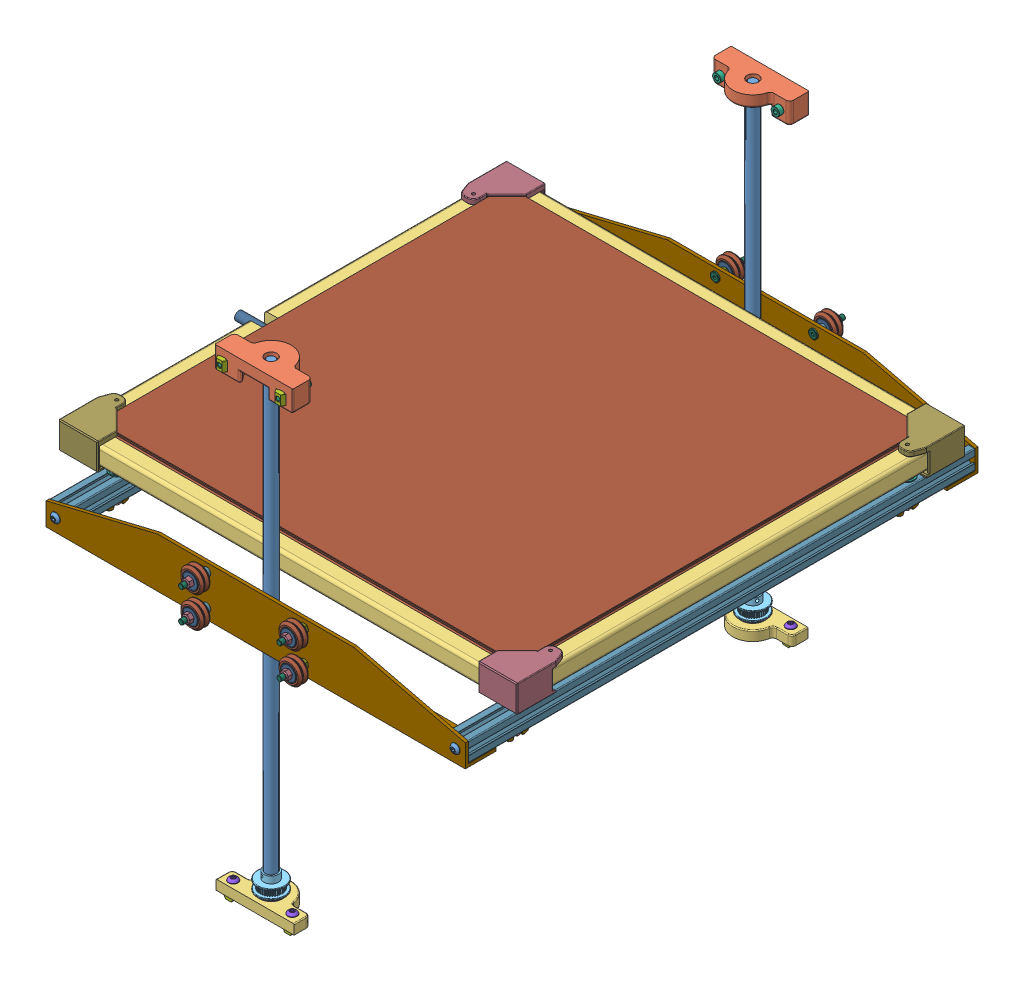
SolidWorks assembly Z_Bed_Assembly, configuration Default. Lengths in mm.
Overall size (485 491.92 579.5).
165 component instances, 32 part files, 17 mates.
Components (placement in the parent):
- Z_Axis_Module-1: Z_Axis_Module [Default] at origin size (80 491.92 43.77)
  - 12mm_Leadscrew-1: 12mm_Leadscrew [Default] at (0 243.6 0) x (0.985154 0 0.171673) z (-0.171673 0 0.985154) size (12 480 12)
  - Z_Leadscrew_Bearing_Holder_Top-1: Z_Leadscrew_Bearing_Holder_Top [Default] at (0 485.6 0) x (-1 0 0) z (0 0 1) size (80 22.17 38.27)
  - Z_Leadscrew_Bearing_Holder_Base-1: Z_Leadscrew_Bearing_Holder_Base [Default] at origin size (80 10 37)
  - 6082Z-8x22x7-1: 6082Z-8x22x7 [6082Z-8x22x7] at (0 480.6 0) x (-0.837169 0 -0.546944) z (0 -1 0) size (22 22 7)
  - 6082Z-8x22x7-2: 6082Z-8x22x7 [6082Z-8x22x7] at (0 4 0) x (1 0 0) z (0 1 0) size (22 22 7)
  - GT2_Aluminum_Timing_Pulley_36_Tooth-1: GT2_Aluminum_Timing_Pulley_36_Tooth [Default] at (0 29.6 0) x (-0.337691 0 0.941257) z (0.941257 0 0.337691) size (28.13 17.5 28.13)
  - 5mmX25mm_Sockethead(McMaster_91290A252)-1: 5mmX25mm_Sockethead(McMaster_91290A252) [91290A252] at (30 474.6 22.7241) size (8.5 8.5 30.5)
  - 5mmX25mm_Sockethead(McMaster_91290A252)-2: 5mmX25mm_Sockethead(McMaster_91290A252) [91290A252] at (-30 474.6 22.7241) size (8.5 8.5 30.5)
  - HNTTSN5-5-1: HNTTSN5-5 [Default] at (-30 474.6 18.9241) x (0 0 -1) z (0 1 0) size (4.3 10 10)
  - HNTTSN5-5-2: HNTTSN5-5 [Default] at (30 474.6 18.9241) x (0 0 -1) z (0 1 0) size (4.3 10 10)
  - HNTTSN5-5-3: HNTTSN5-5 [Default] at (-29.9966 -1.2 8.862) x (0 1 0) z (0 0 1) size (4.3 10 10)
  - HNTTSN5-5-4: HNTTSN5-5 [Default] at (30 -1.2 8.2271) x (0 1 0) z (0 0 1) size (4.3 10 10)
  - 5mmX16mm_Buttonhead(McMaster_91239A232)-1: 5mmX16mm_Buttonhead(McMaster_91239A232) [91239A232] at (30 12.75 8.2271) x (0.745488 0 0.666519) z (0 1 0) size (9.5 9.5 19.24)
  - 5mmX16mm_Buttonhead(McMaster_91239A232)-2: 5mmX16mm_Buttonhead(McMaster_91239A232) [91239A232] at (-29.9966 12.75 8.862) x (0.982416 0 0.186707) z (0 1 0) size (9.5 9.5 19.24)
- Z_Axis_Module-2: Z_Axis_Module [Default] at (0 0 -494.1) x (-1 0 0) z (0 0 -1) size (80 491.92 43.77)
  - 12mm_Leadscrew-1: 12mm_Leadscrew [Default] at (0 243.6 0) x (0.985154 0 0.171673) z (-0.171673 0 0.985154) size (12 480 12)
  - Z_Leadscrew_Bearing_Holder_Top-1: Z_Leadscrew_Bearing_Holder_Top [Default] at (0 485.6 0) x (-1 0 0) z (0 0 1) size (80 22.17 38.27)
  - Z_Leadscrew_Bearing_Holder_Base-1: Z_Leadscrew_Bearing_Holder_Base [Default] at origin size (80 10 37)
  - 6082Z-8x22x7-1: 6082Z-8x22x7 [6082Z-8x22x7] at (0 480.6 0) x (-0.837169 0 -0.546944) z (0 -1 0) size (22 22 7)
  - 6082Z-8x22x7-2: 6082Z-8x22x7 [6082Z-8x22x7] at (0 4 0) x (1 0 0) z (0 1 0) size (22 22 7)
  - GT2_Aluminum_Timing_Pulley_36_Tooth-1: GT2_Aluminum_Timing_Pulley_36_Tooth [Default] at (0 29.6 0) x (-0.337691 0 0.941257) z (0.941257 0 0.337691) size (28.13 17.5 28.13)
  - 5mmX25mm_Sockethead(McMaster_91290A252)-1: 5mmX25mm_Sockethead(McMaster_91290A252) [91290A252] at (30 474.6 22.7241) size (8.5 8.5 30.5)
  - 5mmX25mm_Sockethead(McMaster_91290A252)-2: 5mmX25mm_Sockethead(McMaster_91290A252) [91290A252] at (-30 474.6 22.7241) size (8.5 8.5 30.5)
  - HNTTSN5-5-1: HNTTSN5-5 [Default] at (-30 474.6 18.9241) x (0 0 -1) z (0 1 0) size (4.3 10 10)
  - HNTTSN5-5-2: HNTTSN5-5 [Default] at (30 474.6 18.9241) x (0 0 -1) z (0 1 0) size (4.3 10 10)
  - HNTTSN5-5-3: HNTTSN5-5 [Default] at (-29.9966 -1.2 8.862) x (0 1 0) z (0 0 1) size (4.3 10 10)
  - HNTTSN5-5-4: HNTTSN5-5 [Default] at (30 -1.2 8.2271) x (0 1 0) z (0 0 1) size (4.3 10 10)
  - 5mmX16mm_Buttonhead(McMaster_91239A232)-1: 5mmX16mm_Buttonhead(McMaster_91239A232) [91239A232] at (30 12.75 8.2271) x (0.745488 0 0.666519) z (0 1 0) size (9.5 9.5 19.24)
  - 5mmX16mm_Buttonhead(McMaster_91239A232)-2: 5mmX16mm_Buttonhead(McMaster_91239A232) [91239A232] at (-29.9966 12.75 8.862) x (0.982416 0 0.186707) z (0 1 0) size (9.5 9.5 19.24)
- Z_Gantry_Angle_Plate-1: Z_Gantry_Angle_Plate [Default] at (0 234.9034 15.875) x (-1 0 0) z (0 0 1) size (430 66.25 58.58)
  - Z_Gantry_Plate-1: Z_Gantry_Plate [Default] at origin size (430 50.8 31.75)
  - Dual_V_Wheel_Bolt_Assembly-1: Dual_V_Wheel_Bolt_Assembly [Default] at (50 -42.8 -4.675) x (-0.831081 0.556151 0) z (0.556151 0.831081 0) size (24.11 31.5 24.11) (flexible)
    - Ball_Bearing_625_2RS-1: Ball_Bearing_625_2RS [Défaut] at (0 13.525 0) x (-1 0 0) z (0 0 1) size (16 5 16)
    - Ball_Bearing_625_2RS-2: Ball_Bearing_625_2RS [Défaut] at (0 19.525 0) x (-0.965595 0 -0.260051) z (-0.260051 0 0.965595) size (16 5 16)
    - Dual_V_Wheel_Delrin_(5mm_Bore)-1: Dual_V_Wheel_Delrin_(5mm_Bore) [Défaut] at (0 11.41 0) x (0.999956 0 0.009415) z (-0.009415 0 0.999956) size (23.89 10.23 23.89)
    - Precision_Shim_10x5x1mm-1: Precision_Shim_10x5x1mm [Default] at (0 16.525 0) x (-0.674323 0 -0.738436) z (-0.738436 0 0.674323) size (10 1 10)
    - Nylon_Insert_Hex_Locknut_5mm-1: Nylon_Insert_Hex_Locknut_5mm [Default] at (0 22.025 0) x (0.336542 0 0.941668) z (-0.941668 0 0.336542) size (8 4.99 9.24)
    - Aluminium_Spacer-1: Aluminium_Spacer [Défaut] at (0 7.85 0) x (-0.619579 0 0.784934) z (0 -1 0) size (8 8 6.35)
    - M5_Low_Profile_Screw_30mm-1: M5_Low_Profile_Screw_30mm [Default] at origin size (9 31.5 9)
  - Dual_V_Wheel_Bolt_Assembly-2: Dual_V_Wheel_Bolt_Assembly [Default] at (50 -11.175 -4.675) x (0.333901 -0.942608 0) z (-0.942608 -0.333901 0) size (29.34 31.5 29.34) (flexible)
    - Ball_Bearing_625_2RS-1: Ball_Bearing_625_2RS [Défaut] at (0 13.525 0) x (-1 0 0) z (0 0 1) size (16 5 16)
    - Ball_Bearing_625_2RS-2: Ball_Bearing_625_2RS [Défaut] at (0 19.525 0) x (-0.965595 0 -0.260051) z (-0.260051 0 0.965595) size (16 5 16)
    - Dual_V_Wheel_Delrin_(5mm_Bore)-1: Dual_V_Wheel_Delrin_(5mm_Bore) [Défaut] at (0 11.41 0) x (0.964694 0 -0.263375) z (0.263375 0 0.964694) size (23.89 10.23 23.89)
    - Precision_Shim_10x5x1mm-1: Precision_Shim_10x5x1mm [Default] at (0 16.525 0) x (-0.674323 0 -0.738436) z (-0.738436 0 0.674323) size (10 1 10)
    - Nylon_Insert_Hex_Locknut_5mm-1: Nylon_Insert_Hex_Locknut_5mm [Default] at (0 22.025 0) x (0.457359 0 0.889282) z (-0.889282 0 0.457359) size (8 4.99 9.24)
    - Aluminium_Spacer-1: Aluminium_Spacer [Défaut] at (0 7.85 0) x (0.780963 0 0.624577) z (0 -1 0) size (8 8 6.35)
    - M5_Low_Profile_Screw_30mm-1: M5_Low_Profile_Screw_30mm [Default] at origin size (9 31.5 9)
  - Dual_V_Wheel_Bolt_Assembly_Eccentric-1: Dual_V_Wheel_Bolt_Assembly_Eccentric [Default] at (-50.7692 -11.3552 -4.675) x (1 0 0) z (0 -1 0) size (27.28 31.5 27.28) (flexible)
    - Ball_Bearing_625_2RS-1: Ball_Bearing_625_2RS [Défaut] at (0 13.525 0) x (-1 0 0) z (0 0 1) size (16 5 16)
    - Ball_Bearing_625_2RS-2: Ball_Bearing_625_2RS [Défaut] at (0 19.525 0) x (-0.965595 0 -0.260051) z (-0.260051 0 0.965595) size (16 5 16)
    - Dual_V_Wheel_Delrin_(5mm_Bore)-1: Dual_V_Wheel_Delrin_(5mm_Bore) [Défaut] at (0 11.41 0) x (0.988093 0 -0.153859) z (0.153859 0 0.988093) size (23.89 10.23 23.89)
    - Precision_Shim_10x5x1mm-1: Precision_Shim_10x5x1mm [Default] at (0 16.525 0) x (-0.674323 0 -0.738436) z (-0.738436 0 0.674323) size (10 1 10)
    - Nylon_Insert_Hex_Locknut_5mm-1: Nylon_Insert_Hex_Locknut_5mm [Default] at (0 22.025 0) x (0.336542 0 0.941668) z (-0.941668 0 0.336542) size (8 4.99 9.24)
    - M5_Low_Profile_Screw_30mm-1: M5_Low_Profile_Screw_30mm [Default] at origin size (9 31.5 9)
    - Eccentric_Spacer-1: Eccentric_Spacer [Défaut] at (0.7692 4.675 -0.1802) x (-0.228054 0 -0.973648) z (0 1 0) size (9.99 7.87 7.62)
  - Dual_V_Wheel_Bolt_Assembly_Eccentric-2: Dual_V_Wheel_Bolt_Assembly_Eccentric [Default] at (-50.7252 -43.1133 -4.675) x (1 0 0) z (0 -1 0) size (33.21 31.5 33.21) (flexible)
    - Ball_Bearing_625_2RS-1: Ball_Bearing_625_2RS [Défaut] at (0 13.525 0) x (-1 0 0) z (0 0 1) size (16 5 16)
    - Ball_Bearing_625_2RS-2: Ball_Bearing_625_2RS [Défaut] at (0 19.525 0) x (-0.965595 0 -0.260051) z (-0.260051 0 0.965595) size (16 5 16)
    - Dual_V_Wheel_Delrin_(5mm_Bore)-1: Dual_V_Wheel_Delrin_(5mm_Bore) [Défaut] at (0 11.41 0) x (0.565015 0 -0.825081) z (0.825081 0 0.565015) size (23.89 10.23 23.89)
    - Precision_Shim_10x5x1mm-1: Precision_Shim_10x5x1mm [Default] at (0 16.525 0) x (-0.674323 0 -0.738436) z (-0.738436 0 0.674323) size (10 1 10)
    - Nylon_Insert_Hex_Locknut_5mm-1: Nylon_Insert_Hex_Locknut_5mm [Default] at (0 22.025 0) x (0.336542 0 0.941668) z (-0.941668 0 0.336542) size (8 4.99 9.24)
    - M5_Low_Profile_Screw_30mm-1: M5_Low_Profile_Screw_30mm [Default] at origin size (9 31.5 9)
    - Eccentric_Spacer-1: Eccentric_Spacer [Défaut] at (0.7252 4.675 -0.3133) x (-0.396609 0 -0.917988) z (0 1 0) size (9.99 7.87 7.62)
  - MTSRN12-1: MTSRN12 [Default] at (0 5 -15.875) x (0 -1 0) z (0 0 1) size (30 44 23)
  - HNTTSN5-5-1: HNTTSN5-5 [Default] at (-205 -4.375 -11.176) x (0 1 0) z (0 0 1) size (4.3 10 10)
  - HNTTSN5-5-3: HNTTSN5-5 [Default] at (-205 -4.375 -25.176) x (0 1 0) z (0 0 1) size (4.3 10 10)
  - HNTTSN5-5-4: HNTTSN5-5 [Default] at (205 -4.375 -11.176) x (0 1 0) z (0 0 1) size (4.3 10 10)
  - HNTTSN5-5-6: HNTTSN5-5 [Default] at (205 -4.375 -25.176) x (0 1 0) z (0 0 1) size (4.3 10 10)
  - 5mmX8mm_Buttonhead(McMaster_94500A230)-7: 5mmX8mm_Buttonhead(McMaster_94500A230) [94500A230] at (205 2.75 -25.176) x (0.075751 0 -0.997127) z (0 1 0) size (9.5 9.5 11.19)
  - 5mmX8mm_Buttonhead(McMaster_94500A230)-8: 5mmX8mm_Buttonhead(McMaster_94500A230) [94500A230] at (205 2.75 -11.176) x (1 0 0) z (0 1 0) size (9.5 9.5 11.19)
  - 5mmX10mm_Buttonhead(McMaster_91239A224)-3: 5mmX10mm_Buttonhead(McMaster_91239A224) [91239A224] at (205 -13.175 2.75) size (9.5 9.5 13.21)
  - 5mmX10mm_Buttonhead(McMaster_91239A224)-4: 5mmX10mm_Buttonhead(McMaster_91239A224) [91239A224] at (-205 -13.175 2.75) size (9.5 9.5 13.21)
  - 5mmX8mm_Buttonhead(McMaster_94500A230)-5: 5mmX8mm_Buttonhead(McMaster_94500A230) [94500A230] at (-205 2.75 -25.176) x (1 0 0) z (0 1 0) size (9.5 9.5 11.19)
  - 5mmX8mm_Buttonhead(McMaster_94500A230)-6: 5mmX8mm_Buttonhead(McMaster_94500A230) [94500A230] at (-205 2.75 -11.176) x (1 0 0) z (0 1 0) size (9.5 9.5 11.19)
- Z_Gantry_Angle_Plate-2: Z_Gantry_Angle_Plate [Default] at (0 234.9034 -509.975) x (1 0 0) z (0 0 -1) size (430 66.25 58.58)
  - Z_Gantry_Plate-1: Z_Gantry_Plate [Default] at origin size (430 50.8 31.75)
  - Dual_V_Wheel_Bolt_Assembly-1: Dual_V_Wheel_Bolt_Assembly [Default] at (50 -42.8 -4.675) x (-0.831081 0.556151 0) z (0.556151 0.831081 0) size (24.11 31.5 24.11) (flexible)
    - Ball_Bearing_625_2RS-1: Ball_Bearing_625_2RS [Défaut] at (0 13.525 0) x (-1 0 0) z (0 0 1) size (16 5 16)
    - Ball_Bearing_625_2RS-2: Ball_Bearing_625_2RS [Défaut] at (0 19.525 0) x (-0.965595 0 -0.260051) z (-0.260051 0 0.965595) size (16 5 16)
    - Dual_V_Wheel_Delrin_(5mm_Bore)-1: Dual_V_Wheel_Delrin_(5mm_Bore) [Défaut] at (0 11.41 0) x (0.999956 0 0.009415) z (-0.009415 0 0.999956) size (23.89 10.23 23.89)
    - Precision_Shim_10x5x1mm-1: Precision_Shim_10x5x1mm [Default] at (0 16.525 0) x (-0.674323 0 -0.738436) z (-0.738436 0 0.674323) size (10 1 10)
    - Nylon_Insert_Hex_Locknut_5mm-1: Nylon_Insert_Hex_Locknut_5mm [Default] at (0 22.025 0) x (0.336542 0 0.941668) z (-0.941668 0 0.336542) size (8 4.99 9.24)
    - Aluminium_Spacer-1: Aluminium_Spacer [Défaut] at (0 7.85 0) x (-0.619579 0 0.784934) z (0 -1 0) size (8 8 6.35)
    - M5_Low_Profile_Screw_30mm-1: M5_Low_Profile_Screw_30mm [Default] at origin size (9 31.5 9)
  - Dual_V_Wheel_Bolt_Assembly-2: Dual_V_Wheel_Bolt_Assembly [Default] at (50 -11.175 -4.675) x (0.333901 -0.942608 0) z (-0.942608 -0.333901 0) size (29.34 31.5 29.34) (flexible)
    - Ball_Bearing_625_2RS-1: Ball_Bearing_625_2RS [Défaut] at (0 13.525 0) x (-1 0 0) z (0 0 1) size (16 5 16)
    - Ball_Bearing_625_2RS-2: Ball_Bearing_625_2RS [Défaut] at (0 19.525 0) x (-0.965595 0 -0.260051) z (-0.260051 0 0.965595) size (16 5 16)
    - Dual_V_Wheel_Delrin_(5mm_Bore)-1: Dual_V_Wheel_Delrin_(5mm_Bore) [Défaut] at (0 11.41 0) x (0.964694 0 -0.263375) z (0.263375 0 0.964694) size (23.89 10.23 23.89)
    - Precision_Shim_10x5x1mm-1: Precision_Shim_10x5x1mm [Default] at (0 16.525 0) x (-0.674323 0 -0.738436) z (-0.738436 0 0.674323) size (10 1 10)
    - Nylon_Insert_Hex_Locknut_5mm-1: Nylon_Insert_Hex_Locknut_5mm [Default] at (0 22.025 0) x (0.457359 0 0.889282) z (-0.889282 0 0.457359) size (8 4.99 9.24)
    - Aluminium_Spacer-1: Aluminium_Spacer [Défaut] at (0 7.85 0) x (0.780963 0 0.624577) z (0 -1 0) size (8 8 6.35)
    - M5_Low_Profile_Screw_30mm-1: M5_Low_Profile_Screw_30mm [Default] at origin size (9 31.5 9)
  - Dual_V_Wheel_Bolt_Assembly_Eccentric-1: Dual_V_Wheel_Bolt_Assembly_Eccentric [Default] at (-50.7692 -11.3552 -4.675) x (1 0 0) z (0 -1 0) size (27.28 31.5 27.28) (flexible)
    - Ball_Bearing_625_2RS-1: Ball_Bearing_625_2RS [Défaut] at (0 13.525 0) x (-1 0 0) z (0 0 1) size (16 5 16)
    - Ball_Bearing_625_2RS-2: Ball_Bearing_625_2RS [Défaut] at (0 19.525 0) x (-0.965595 0 -0.260051) z (-0.260051 0 0.965595) size (16 5 16)
    - Dual_V_Wheel_Delrin_(5mm_Bore)-1: Dual_V_Wheel_Delrin_(5mm_Bore) [Défaut] at (0 11.41 0) x (0.988093 0 -0.153859) z (0.153859 0 0.988093) size (23.89 10.23 23.89)
    - Precision_Shim_10x5x1mm-1: Precision_Shim_10x5x1mm [Default] at (0 16.525 0) x (-0.674323 0 -0.738436) z (-0.738436 0 0.674323) size (10 1 10)
    - Nylon_Insert_Hex_Locknut_5mm-1: Nylon_Insert_Hex_Locknut_5mm [Default] at (0 22.025 0) x (0.336542 0 0.941668) z (-0.941668 0 0.336542) size (8 4.99 9.24)
    - M5_Low_Profile_Screw_30mm-1: M5_Low_Profile_Screw_30mm [Default] at origin size (9 31.5 9)
    - Eccentric_Spacer-1: Eccentric_Spacer [Défaut] at (0.7692 4.675 -0.1802) x (-0.228054 0 -0.973648) z (0 1 0) size (9.99 7.87 7.62)
  - Dual_V_Wheel_Bolt_Assembly_Eccentric-2: Dual_V_Wheel_Bolt_Assembly_Eccentric [Default] at (-50.7252 -43.1133 -4.675) x (1 0 0) z (0 -1 0) size (33.21 31.5 33.21) (flexible)
    - Ball_Bearing_625_2RS-1: Ball_Bearing_625_2RS [Défaut] at (0 13.525 0) x (-1 0 0) z (0 0 1) size (16 5 16)
    - Ball_Bearing_625_2RS-2: Ball_Bearing_625_2RS [Défaut] at (0 19.525 0) x (-0.965595 0 -0.260051) z (-0.260051 0 0.965595) size (16 5 16)
    - Dual_V_Wheel_Delrin_(5mm_Bore)-1: Dual_V_Wheel_Delrin_(5mm_Bore) [Défaut] at (0 11.41 0) x (0.565015 0 -0.825081) z (0.825081 0 0.565015) size (23.89 10.23 23.89)
    - Precision_Shim_10x5x1mm-1: Precision_Shim_10x5x1mm [Default] at (0 16.525 0) x (-0.674323 0 -0.738436) z (-0.738436 0 0.674323) size (10 1 10)
    - Nylon_Insert_Hex_Locknut_5mm-1: Nylon_Insert_Hex_Locknut_5mm [Default] at (0 22.025 0) x (0.336542 0 0.941668) z (-0.941668 0 0.336542) size (8 4.99 9.24)
    - M5_Low_Profile_Screw_30mm-1: M5_Low_Profile_Screw_30mm [Default] at origin size (9 31.5 9)
    - Eccentric_Spacer-1: Eccentric_Spacer [Défaut] at (0.7252 4.675 -0.3133) x (-0.396609 0 -0.917988) z (0 1 0) size (9.99 7.87 7.62)
  - MTSRN12-1: MTSRN12 [Default] at (0 5 -15.875) x (0 -1 0) z (0 0 1) size (30 44 23)
  - HNTTSN5-5-1: HNTTSN5-5 [Default] at (-205 -4.375 -11.176) x (0 1 0) z (0 0 1) size (4.3 10 10)
  - HNTTSN5-5-3: HNTTSN5-5 [Default] at (-205 -4.375 -25.176) x (0 1 0) z (0 0 1) size (4.3 10 10)
  - HNTTSN5-5-4: HNTTSN5-5 [Default] at (205 -4.375 -11.176) x (0 1 0) z (0 0 1) size (4.3 10 10)
  - HNTTSN5-5-6: HNTTSN5-5 [Default] at (205 -4.375 -25.176) x (0 1 0) z (0 0 1) size (4.3 10 10)
  - 5mmX8mm_Buttonhead(McMaster_94500A230)-7: 5mmX8mm_Buttonhead(McMaster_94500A230) [94500A230] at (205 2.75 -25.176) x (0.075751 0 -0.997127) z (0 1 0) size (9.5 9.5 11.19)
  - 5mmX8mm_Buttonhead(McMaster_94500A230)-8: 5mmX8mm_Buttonhead(McMaster_94500A230) [94500A230] at (205 2.75 -11.176) x (1 0 0) z (0 1 0) size (9.5 9.5 11.19)
  - 5mmX10mm_Buttonhead(McMaster_91239A224)-3: 5mmX10mm_Buttonhead(McMaster_91239A224) [91239A224] at (205 -13.175 2.75) size (9.5 9.5 13.21)
  - 5mmX10mm_Buttonhead(McMaster_91239A224)-4: 5mmX10mm_Buttonhead(McMaster_91239A224) [91239A224] at (-205 -13.175 2.75) size (9.5 9.5 13.21)
  - 5mmX8mm_Buttonhead(McMaster_94500A230)-5: 5mmX8mm_Buttonhead(McMaster_94500A230) [94500A230] at (-205 2.75 -25.176) x (1 0 0) z (0 1 0) size (9.5 9.5 11.19)
  - 5mmX8mm_Buttonhead(McMaster_94500A230)-6: 5mmX8mm_Buttonhead(McMaster_94500A230) [94500A230] at (-205 2.75 -11.176) x (1 0 0) z (0 1 0) size (9.5 9.5 11.19)
- Heated_Bed_Assembly-1: Heated_Bed_Assembly [Default] at (0 296.2734 -247.05) size (485 77.32 460)
  - Aluminum_Build_Plate-1: Aluminum_Build_Plate [Default] at origin size (430 6.35 420)
  - MDF_Insulator_Board-1: MDF_Insulator_Board [Default] at (0 -3.175 0) size (464 19.05 454)
  - 5mmX70mm_Flathead(McMaster_92125A219)-1: 5mmX70mm_Flathead(McMaster_92125A219) [92125A219] at (-205 2.875 -200) x (1 0 0) z (0 1 0) size (10 10 70.8)
  - .75L_.5OD_.062Wire(McMaster_9657K292)-1: .75L_.5OD_.062Wire(McMaster_9657K292) [9657K292] at (-205 -37.195 -200) x (1 0 0) z (0 -1 0) size (13.08 13.24 19.84)
  - M5_Oversized_FlatWasher(McMaster_91100A140)-1: M5_Oversized_FlatWasher(McMaster_91100A140) [91100A140] at (-205 -18.145 -200) x (1 0 0) z (0 -1 0) size (15 15 1)
  - M5_Oversized_FlatWasher(McMaster_91100A140)-2: M5_Oversized_FlatWasher(McMaster_91100A140) [91100A140] at (-205 -37.195 -200) x (1 0 0) z (0 1 0) size (15 15 1)
  - 5mmX70mm_Flathead(McMaster_92125A219)-5: 5mmX70mm_Flathead(McMaster_92125A219) [92125A219] at (-205 2.875 200) x (1 0 0) z (0 1 0) size (10 10 70.8)
  - M5_Oversized_FlatWasher(McMaster_91100A140)-3: M5_Oversized_FlatWasher(McMaster_91100A140) [91100A140] at (-205 -38.195 200) x (1 0 0) z (0 -1 0) size (15 15 1)
  - .75L_.5OD_.062Wire(McMaster_9657K292)-2: .75L_.5OD_.062Wire(McMaster_9657K292) [9657K292] at (-205 -37.195 200.0086) x (1 0 0) z (0 -1 0) size (13.08 13.24 19.84)
  - M5_Oversized_FlatWasher(McMaster_91100A140)-4: M5_Oversized_FlatWasher(McMaster_91100A140) [91100A140] at (-205 -17.145 200) x (1 0 0) z (0 1 0) size (15 15 1)
  - 5mmX70mm_Flathead(McMaster_92125A219)-6: 5mmX70mm_Flathead(McMaster_92125A219) [92125A219] at (205 2.875 -200) x (-1 0 0) z (0 1 0) size (10 10 70.8)
  - M5_Oversized_FlatWasher(McMaster_91100A140)-5: M5_Oversized_FlatWasher(McMaster_91100A140) [91100A140] at (205 -38.195 -200) x (-1 0 0) z (0 -1 0) size (15 15 1)
  - .75L_.5OD_.062Wire(McMaster_9657K292)-3: .75L_.5OD_.062Wire(McMaster_9657K292) [9657K292] at (205 -37.195 -200.0086) x (-1 0 0) z (0 -1 0) size (13.08 13.24 19.84)
  - M5_Oversized_FlatWasher(McMaster_91100A140)-6: M5_Oversized_FlatWasher(McMaster_91100A140) [91100A140] at (205 -17.145 -200) x (-1 0 0) z (0 1 0) size (15 15 1)
  - 5mmX70mm_Flathead(McMaster_92125A219)-7: 5mmX70mm_Flathead(McMaster_92125A219) [92125A219] at (205 2.875 200) x (-1 0 0) z (0 1 0) size (10 10 70.8)
  - M5_Oversized_FlatWasher(McMaster_91100A140)-7: M5_Oversized_FlatWasher(McMaster_91100A140) [91100A140] at (205 -37.195 200) x (-1 0 0) z (0 1 0) size (15 15 1)
  - .75L_.5OD_.062Wire(McMaster_9657K292)-4: .75L_.5OD_.062Wire(McMaster_9657K292) [9657K292] at (205 -37.195 200) x (-1 0 0) z (0 -1 0) size (13.08 13.24 19.84)
  - M5_Oversized_FlatWasher(McMaster_91100A140)-8: M5_Oversized_FlatWasher(McMaster_91100A140) [91100A140] at (205 -18.145 200) x (-1 0 0) z (0 -1 0) size (15 15 1)
  - 5mmX30mm_Flathead(McMaster_92125A220)-1: 5mmX30mm_Flathead(McMaster_92125A220) [92125A220] at (205 2.875 0) x (0.851119 0 -0.524972) z (0 1 0) size (10 10 30.56)
  - 5mm_Hex_NyLockNut(McMaster_94205A240)-1: 5mm_Hex_NyLockNut(McMaster_94205A240) [94205A240] at (205 -18.145 0) x (-0.837169 0 -0.546944) z (-0.546944 0 0.837169) size (8 5.15 9.24)
  - M5_Oversized_FlatWasher(McMaster_91100A140)-9: M5_Oversized_FlatWasher(McMaster_91100A140) [91100A140] at (205 -17.145 0) x (1 0 0) z (0 1 0) size (15 15 1)
  - 5mmX30mm_Flathead(McMaster_92125A220)-2: 5mmX30mm_Flathead(McMaster_92125A220) [92125A220] at (-205 2.875 0) x (-0.851119 0 -0.524972) z (0 1 0) size (10 10 30.56)
  - M5_Oversized_FlatWasher(McMaster_91100A140)-10: M5_Oversized_FlatWasher(McMaster_91100A140) [91100A140] at (-205 -18.145 0) x (-1 0 0) z (0 -1 0) size (15 15 1)
  - 5mm_Hex_NyLockNut(McMaster_94205A240)-2: 5mm_Hex_NyLockNut(McMaster_94205A240) [94205A240] at (-205 -18.145 0) x (-0.837169 0 0.546944) z (0.546944 0 0.837169) size (8 5.15 9.24)
  - 5mm_Hex_NyLockNut(McMaster_94205A240)-5: 5mm_Hex_NyLockNut(McMaster_94205A240) [94205A240] at (-205 -3.175 -200) x (-0.837169 0 -0.546944) z (-0.546944 0 0.837169) size (8 5.15 9.24)
  - 5mm_Hex_NyLockNut(McMaster_94205A240)-7: 5mm_Hex_NyLockNut(McMaster_94205A240) [94205A240] at (-205 -3.175 200) x (0.837169 0 -0.546944) z (-0.546944 0 -0.837169) size (8 5.15 9.24)
  - 5mm_Hex_NyLockNut(McMaster_94205A240)-8: 5mm_Hex_NyLockNut(McMaster_94205A240) [94205A240] at (205 -3.175 200) x (0.837169 0 0.546944) z (0.546944 0 -0.837169) size (8 5.15 9.24)
  - 5mm_Hex_NyLockNut(McMaster_94205A240)-9: 5mm_Hex_NyLockNut(McMaster_94205A240) [94205A240] at (205 -3.175 -200) x (-0.837169 0 0.546944) z (0.546944 0 0.837169) size (8 5.15 9.24)
  - 5mm_Wingnut(McMaster_94545A225)-1: 5mm_Wingnut(McMaster_94545A225) [94545A225] at (-205 -59.195 -200) x (0 0 -1) z (0 1 0) size (21.75 10 10.78)
  - M5_Oversized_FlatWasher(McMaster_91100A140)-11: M5_Oversized_FlatWasher(McMaster_91100A140) [91100A140] at (-205 -59.195 -200) x (1 0 0) z (0 -1 0) size (15 15 1)
  - 5mm_Wingnut(McMaster_94545A225)-2: 5mm_Wingnut(McMaster_94545A225) [94545A225] at (-205 -59.195 200) x (0 0 -1) z (0 1 0) size (21.75 10 10.78)
  - M5_Oversized_FlatWasher(McMaster_91100A140)-12: M5_Oversized_FlatWasher(McMaster_91100A140) [91100A140] at (-205 -58.195 200) x (1 0 0) z (0 1 0) size (15 15 1)
  - 5mm_Wingnut(McMaster_94545A225)-3: 5mm_Wingnut(McMaster_94545A225) [94545A225] at (205 -59.195 -200) x (0 0 1) z (0 1 0) size (21.75 10 10.78)
  - M5_Oversized_FlatWasher(McMaster_91100A140)-13: M5_Oversized_FlatWasher(McMaster_91100A140) [91100A140] at (205 -58.195 -200) x (-1 0 0) z (0 1 0) size (15 15 1)
  - M5_Oversized_FlatWasher(McMaster_91100A140)-14: M5_Oversized_FlatWasher(McMaster_91100A140) [91100A140] at (205 -59.195 200) x (-1 0 0) z (0 -1 0) size (15 15 1)
  - 5mm_Wingnut(McMaster_94545A225)-4: 5mm_Wingnut(McMaster_94545A225) [94545A225] at (205 -59.195 200) x (0 0 1) z (0 1 0) size (21.75 10 10.78)
  - 380mmx380mm_800W_120V_Silicone_Heater(Alirubber)-1: 380mmx380mm_800W_120V_Silicone_Heater(Alirubber) [Default] at (0 -3.175 0) x (0 0 -1) z (-1 0 0) size (380 9 440)
  - Window_Glass_420by430-1: Window_Glass_420by430 [Default] at (0 3.175 0) x (0 0 -1) z (0 1 0) size (420 430 2.38)
  - Bed_Glass_Clip-1: Bed_Glass_Clip [Default] at (232 7.655 -227) x (0 0 1) z (0 -1 0) size (53.5 40 27.8)
  - Bed_Glass_Clip-3: Bed_Glass_Clip [Default] at (-232 7.655 227) x (0 0 -1) z (0 -1 0) size (53.5 40 27.8)
  - Bed_Glass_Clip_Mirror-1: Bed_Glass_Clip_Mirror [Default] at (-232 7.655 -233) x (0 0 -1) z (0 -1 0) size (53.5 40 27.8)
  - Bed_Glass_Clip_Mirror-2: Bed_Glass_Clip_Mirror [Default] at (232 7.655 233) x (0 0 1) z (0 -1 0) size (53.5 40 27.8)
- HFS5-2020-519_5-1: HFS5-2020-519_5 [Default] at (205 248.0784 12.7) size (20 20 519.5)
- HFS5-2020-519_5-2: HFS5-2020-519_5 [Default] at (-205 248.0784 12.7) size (20 20 519.5)
Mates (geometry in assembly coordinates):
- Concentric1: concentric aligned: cylinder of Z_Axis_Module-1/12mm_Leadscrew-1 through (0 483.6 0) axis (0 -1 0) radius 6; cylinder of Z_Gantry_Angle_Plate-1/MTSRN12-1 through (0 259.9034 0) axis (0 -1 0) radius 5
- Concentric2: concentric aligned: cylinder of Z_Axis_Module-2/12mm_Leadscrew-1 through (0 483.6 -494.1) axis (0 -1 0) radius 6; cylinder of Z_Gantry_Angle_Plate-2/MTSRN12-1 through (0 259.9034 -494.1) axis (0 -1 0) radius 5
- Coincident1: coincident anti-aligned: plane of Z_Gantry_Angle_Plate-1/Z_Gantry_Plate-1 through (-215 238.0784 12.7) normal (0 0 -1); plane of HFS5-2020-519_5-1 through (196 257.0784 12.7) normal (0 0 1)
- Coincident2: coincident aligned: plane of Z_Gantry_Angle_Plate-1/Z_Gantry_Plate-1 through (215 234.9034 15.875) normal (1 0 0); plane of HFS5-2020-519_5-1 through (215 251.3784 -506.8) normal (1 0 0)
- Concentric3: concentric aligned: cylinder of Z_Gantry_Angle_Plate-1/5mmX10mm_Buttonhead(McMaster_91239A224)-4 through (205 248.0784 18.625) axis (0 0 1) radius 4.75; cylinder of HFS5-2020-519_5-1 through (205 248.0784 -506.8) axis (0 0 1) radius 2.1
- Coincident3: coincident anti-aligned: plane of Z_Gantry_Angle_Plate-1/Z_Gantry_Plate-1 through (-215 238.0784 12.7) normal (0 0 -1); plane of HFS5-2020-519_5-2 through (-214 257.0784 12.7) normal (0 0 1)
- Coincident4: coincident aligned: plane of Z_Gantry_Angle_Plate-1/Z_Gantry_Plate-1 through (-215 234.9034 15.875) normal (-1 0 0); plane of HFS5-2020-519_5-2 through (-215 257.0784 -506.8) normal (-1 0 0)
- Concentric4: concentric aligned: cylinder of Z_Gantry_Angle_Plate-1/5mmX10mm_Buttonhead(McMaster_91239A224)-3 through (-205 248.0784 18.625) axis (0 0 1) radius 4.75; cylinder of HFS5-2020-519_5-2 through (-205 248.0784 -506.8) axis (0 0 1) radius 2.1
- Concentric5: concentric anti-aligned: line of Heated_Bed_Assembly-1/.75L_.5OD_.062Wire(McMaster_9657K292)-4 through (205 259.0784 -47.05) axis (0 -1 0); cylinder of HFS5-2020-519_5-1 through (205 230.7244 -47.05) axis (0 1 0) radius 2.6
- Parallel1: parallel aligned: plane of Heated_Bed_Assembly-1/MDF_Insulator_Board-1 through (232 279.1284 -247.05) normal (1 0 0); plane of HFS5-2020-519_5-1 through (215 251.3784 -506.8) normal (1 0 0)
- Coincident6: coincident anti-aligned: plane of Heated_Bed_Assembly-1/M5_Oversized_FlatWasher(McMaster_91100A140)-7 through (205 258.0784 -47.05) normal (0 -1 0); plane of HFS5-2020-519_5-1 through (214 258.0784 -506.8) normal (0 1 0)
- Parallel2: parallel aligned: plane of Z_Axis_Module-1/Z_Leadscrew_Bearing_Holder_Base-1 through (-40 10 16.4541) normal (0 0 1); plane of Z_Gantry_Angle_Plate-1/Z_Gantry_Plate-1 through (-215 285.7034 15.875) normal (0 0 1)
- Coincident8: coincident aligned: plane of Z_Axis_Module-1/Z_Leadscrew_Bearing_Holder_Base-1 through (0 0 0) normal (0 -1 0); plane of Z_Axis_Module-2/Z_Leadscrew_Bearing_Holder_Base-1 through (0 0 -494.1) normal (0 -1 0)
- Concentric6: concentric anti-aligned: cylinder of Z_Gantry_Angle_Plate-2/5mmX10mm_Buttonhead(McMaster_91239A224)-3 through (205 248.0784 -512.725) axis (0 0 -1) radius 4.75; cylinder of HFS5-2020-519_5-1 through (205 248.0784 -506.8) axis (0 0 1) radius 2.1
- Concentric7: concentric anti-aligned: cylinder of Z_Gantry_Angle_Plate-2/5mmX10mm_Buttonhead(McMaster_91239A224)-4 through (-205 248.0784 -512.725) axis (0 0 -1) radius 4.75; cylinder of HFS5-2020-519_5-2 through (-205 248.0784 -506.8) axis (0 0 1) radius 2.1
- Coincident9: coincident anti-aligned: plane of Z_Gantry_Angle_Plate-2/Z_Gantry_Plate-1 through (215 238.0784 -506.8) normal (0 0 1); plane of HFS5-2020-519_5-2 through (-214 257.0784 -506.8) normal (0 0 -1)
- Parallel3: parallel anti-aligned: plane of Z_Axis_Module-1/Z_Leadscrew_Bearing_Holder_Top-1 through (40 473.6 17.7241) normal (0 0 1); plane of Z_Axis_Module-2/Z_Leadscrew_Bearing_Holder_Top-1 through (-40 473.6 -511.8241) normal (0 0 -1)
